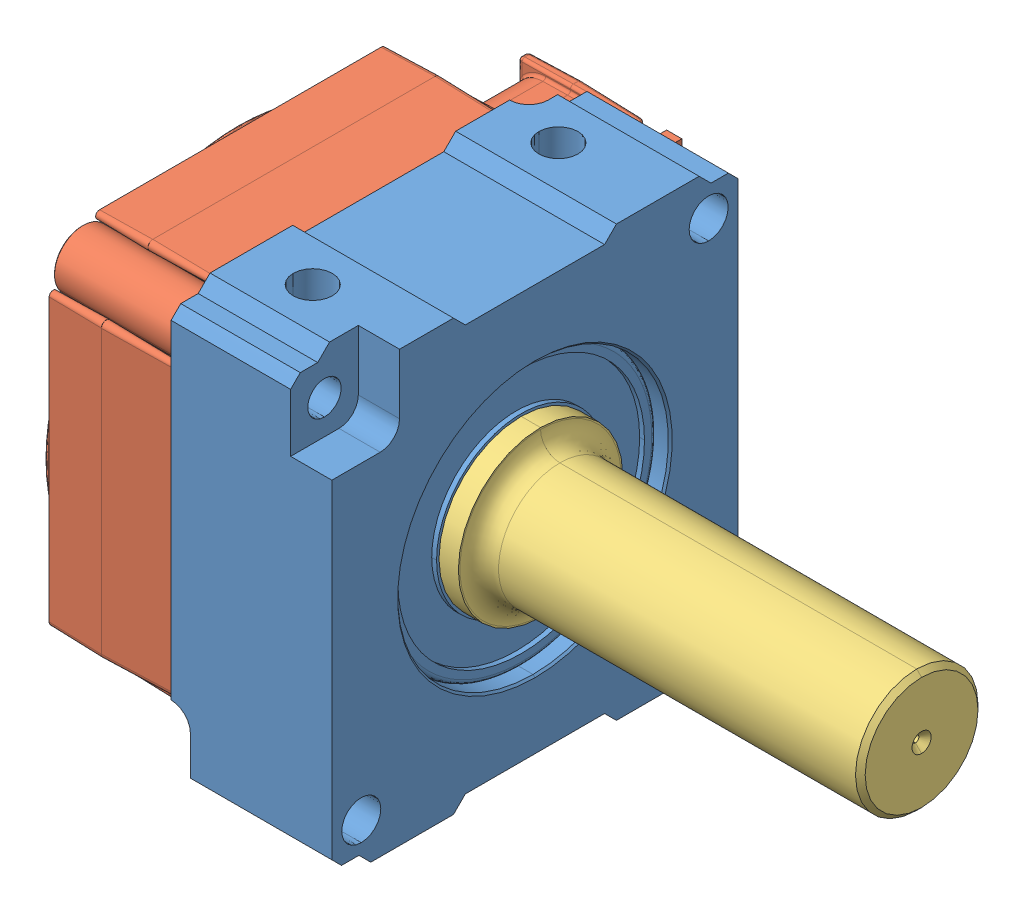
SolidWorks assembly Output Housing, configuration Default. Lengths in mm.
Overall size (75.7 44.45 56.32).
3 component instances, 3 part files, 6 mates.
Components (placement in the parent):
- Housing-1: Housing [Default] at (19.8785 -6.4219 -11.5232) size (18.13 44.45 42)
- Encoder.step-1: Encoder.step [Default] at (12.6785 15.8031 -11.5232) x (0 0 1) z (-1 0 0) size (56.32 42 21.21)
- Gearbox_output_shaft-1: Gearbox_output_shaft [Default] at origin size (63.51 17 17)
Mates (geometry in assembly coordinates):
- Concentric2: concentric anti-aligned: cylinder of Housing-1 through (20.0787 15.8031 -11.5232) axis (-1 0 0) radius 7.5; cylinder of Encoder.step-1 through (0.7785 15.8031 -11.5232) axis (1 0 0) radius 4.025
- Concentric4: concentric anti-aligned: cylinder of Housing-1 through (32.2395 -1.6969 -29.0232) axis (1 0 0) radius 1.7272; cylinder of Encoder.step-1 through (6.1524 -1.6969 -29.0232) axis (-1 0 0) radius 2.2479
- Coincident2: coincident anti-aligned: plane of Housing-1 through (19.8785 15.8031 -11.5232) normal (-1 0 0); plane of Encoder.step-1 through (19.8785 0.7373 -27.3567) normal (1 0 0)
- Concentric5: concentric aligned: cylinder of Housing-1 through (28.0787 15.8031 -11.5232) axis (-1 0 0) radius 7.5; cylinder of Gearbox_output_shaft-1 through (76.4787 15.8031 -11.5232) axis (-1 0 0) radius 6.335
- Coincident3: coincident anti-aligned: plane of Housing-1 through (35.0787 23.3031 -11.5232) normal (1 0 0); plane of Gearbox_output_shaft-1 through (35.0787 15.8031 -11.5232) normal (-1 0 0)
- Parallel1: parallel anti-aligned: plane of Housing-1 through (18.3785 36.8031 -20.2232) normal (0 1 0); plane of Gearbox_output_shaft-1 through (42.0787 17.3906 -16.1079) normal (0 -1 0)
